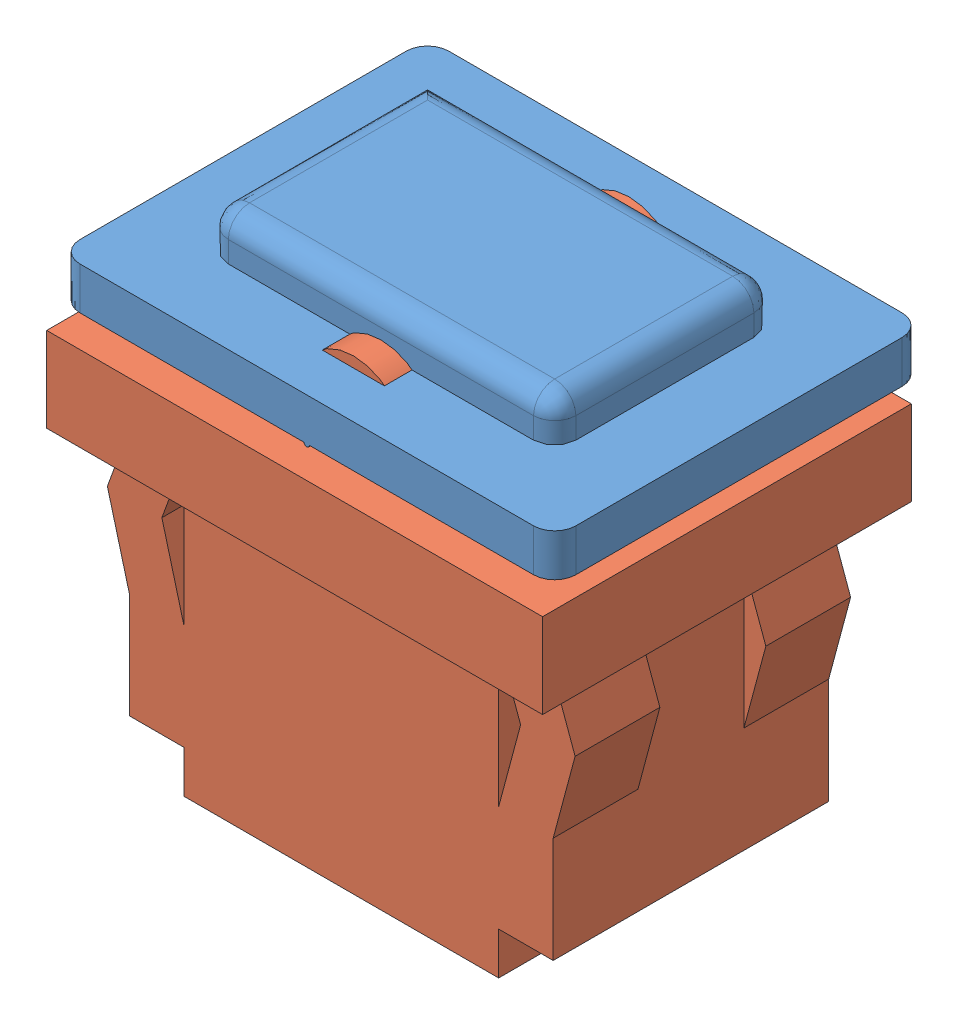
SolidWorks assembly GRB066B802BR1, configuration Default. Lengths in mm.
Overall size (23.97 23.5 17.4).
2 component instances, 2 part files, 5 mates.
Components (placement in the parent):
- Rocker^GRB066B802BR1-1: Rocker^GRB066B802BR1 [Default] at (0 5.5 0) size (23.4 4.12 17.4) (virtual)
- Base^GRB066B802BR1-1: Base^GRB066B802BR1 [Default] at (-0.5714 -14 0) size (23.4 22 17.4) (virtual)
Mates (geometry in assembly coordinates):
- Concentric1: concentric anti-aligned: circle of Rocker^GRB066B802BR1-1; circle of Base^GRB066B802BR1-1
- Coincident1: coincident aligned: plane of Rocker^GRB066B802BR1-1 through (-11.7 7.5 -8.7) normal (0 0 -1); plane of Base^GRB066B802BR1-1 through (-12.2714 4 -8.7) normal (0 0 -1)
- Coincident2: coincident anti-aligned: plane of Base^GRB066B802BR1-1 through (-0.5714 0 0) normal (0 -1 0); plane of assembly through (0 0 0) normal (0 1 0)
- Coincident3: coincident aligned: plane of Rocker^GRB066B802BR1-1 through (0 5.5 0) normal (0 0 1); plane of assembly through (0 0 0) normal (0 0 1)
- Coincident4: coincident aligned: plane of Rocker^GRB066B802BR1-1 through (0 5.5 0) normal (1 0 0); plane of assembly through (0 0 0) normal (1 0 0)
